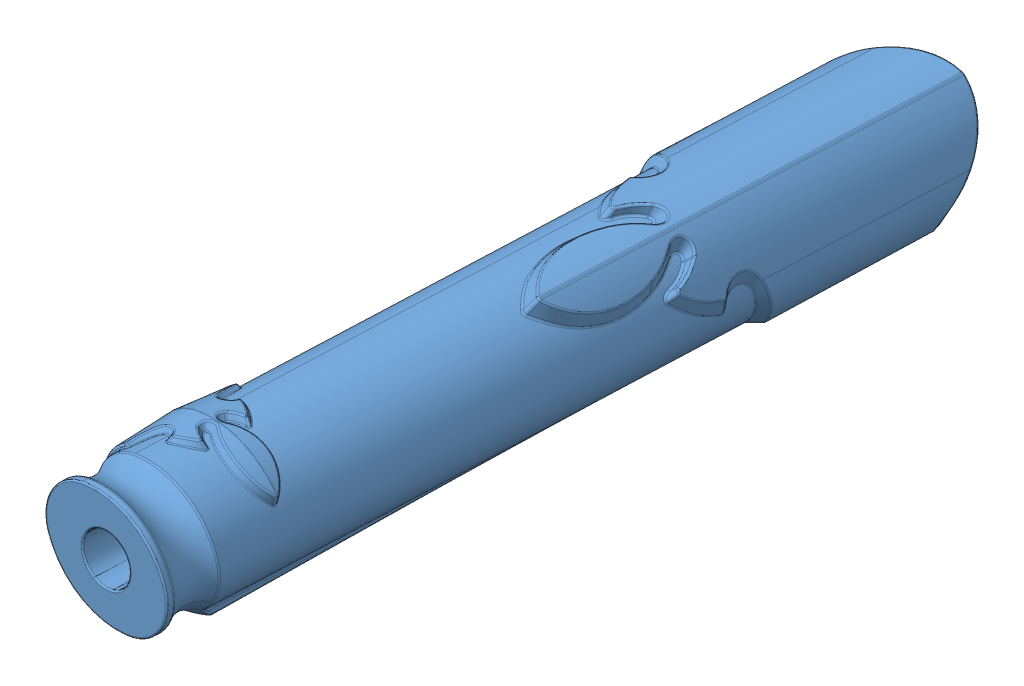
SolidWorks assembly Couteau CH 16-12-2022.STEP, configuration Default. Lengths in mm.
Overall size (27.25 27.55 111.42).
2 component instances, 2 part files, 0 mates.
Components (placement in the parent):
- Couteau CH version 3 modif 5D.STEP-1: Couteau CH version 3 modif 5D.STEP [Default] at (0 7.408 0) x (0.48678 0.873395 -0.015064) z (-0.015064 0.025635 0.999558) size (17.38 19.6 110.7)
- Couteau CH- lame couteau 1.STEP-1: Couteau CH- lame couteau 1.STEP [Default] at (-0.1205 7.6131 7.9965) x (0.48678 0.873395 -0.015064) z (-0.015064 0.025635 0.999558) size (14 22.14 180.89) (hidden)
